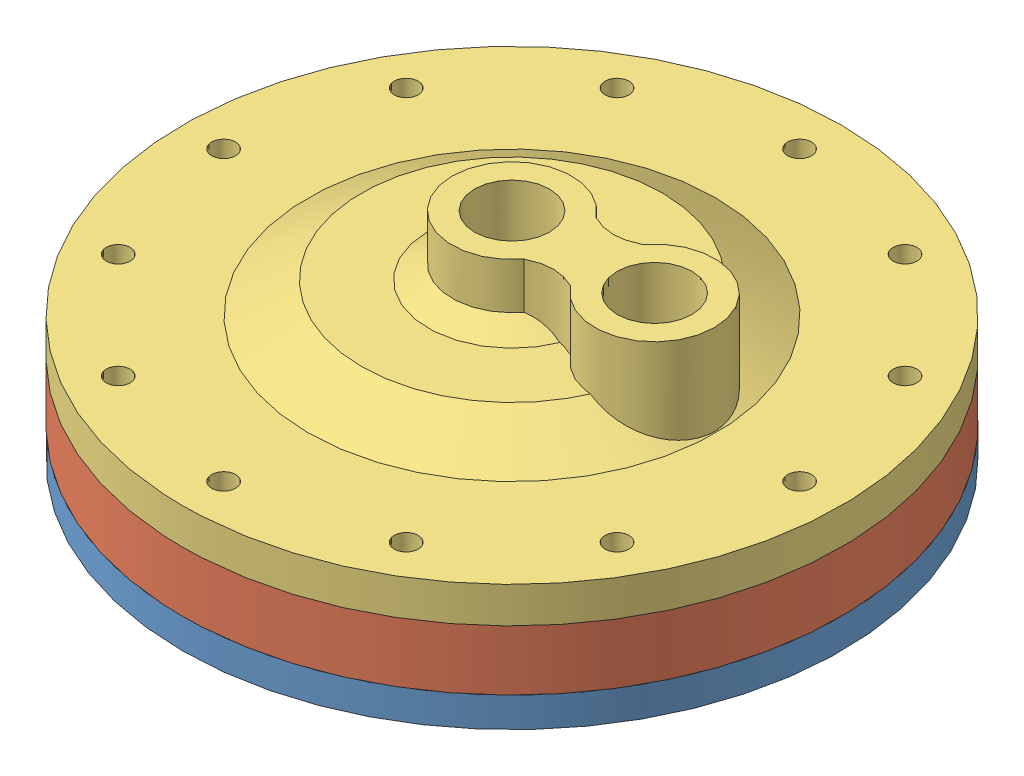
SolidWorks assembly Injector Assembly V4-2_12x_Bigger manifold, configuration Default. Lengths in mm.
Overall size (139.7 45.9 139.7).
3 component instances, 3 part files, 10 mates.
Components (placement in the parent):
- Injector V4-1: Injector V4 [Default] x (1 0 0) z (0 0 -1) size (139.7 15.63 139.7)
- Distribution Plate V4-1: Distribution Plate V4 [Default] at origin size (139.7 22.23 139.7)
- Top Plate V4-1: Top Plate V4 [Default] at (0 12.7 0) size (139.7 26.85 139.7)
Mates (geometry in assembly coordinates):
- Coincident1: coincident aligned: plane of Injector V4-1 through (0 0 0) normal (0 1 0)
- Coincident2: coincident anti-aligned: plane of Injector V4-1 through (0 0 0) normal (0 0 -1)
- Coincident3: coincident aligned: plane of Injector V4-1 through (0 0 0) normal (1 0 0)
- Coincident4: coincident anti-aligned: plane of Injector V4-1 through (0 -6.35 0) normal (0 -1 0); plane of FLANGE-1 through (0 -6.35 0) normal (0 1 0)
- Concentric1: concentric anti-aligned: cylinder of Injector V4-1 through (0 -6.35 0) axis (0 1 0) radius 69.85; cylinder of FLANGE-1 through (0 -26.67 0) axis (0 -1 0) radius 73.025
- Concentric2: concentric aligned: cylinder of Injector V4-1 through (30.48 -6.35 -52.7929) axis (0 1 0) radius 3.2639; cylinder of FLANGE-1 through (30.48 -25.4 -52.7929) axis (0 1 0) radius 2.4892
- Concentric3: concentric aligned: cylinder of FLANGE-1 through (0 -26.67 0) axis (0 -1 0) radius 73.025; cylinder of Distribution Plate V4-1 through (0 12.7 0) axis (0 -1 0) radius 69.85
- Coincident5: coincident anti-aligned: plane of Injector V4-1 through (0 0 0) normal (0 1 0); plane of Distribution Plate V4-1 through (0 0 0) normal (0 -1 0)
- Concentric4: concentric aligned: cylinder of Distribution Plate V4-1 through (0 12.7 0) axis (0 -1 0) radius 69.85; cylinder of Top Plate V4-1 through (0 20.32 0) axis (0 -1 0) radius 69.85
- Coincident6: coincident anti-aligned: plane of Distribution Plate V4-1 through (0 12.7 0) normal (0 1 0); plane of Top Plate V4-1 through (0 12.7 0) normal (0 -1 0)
